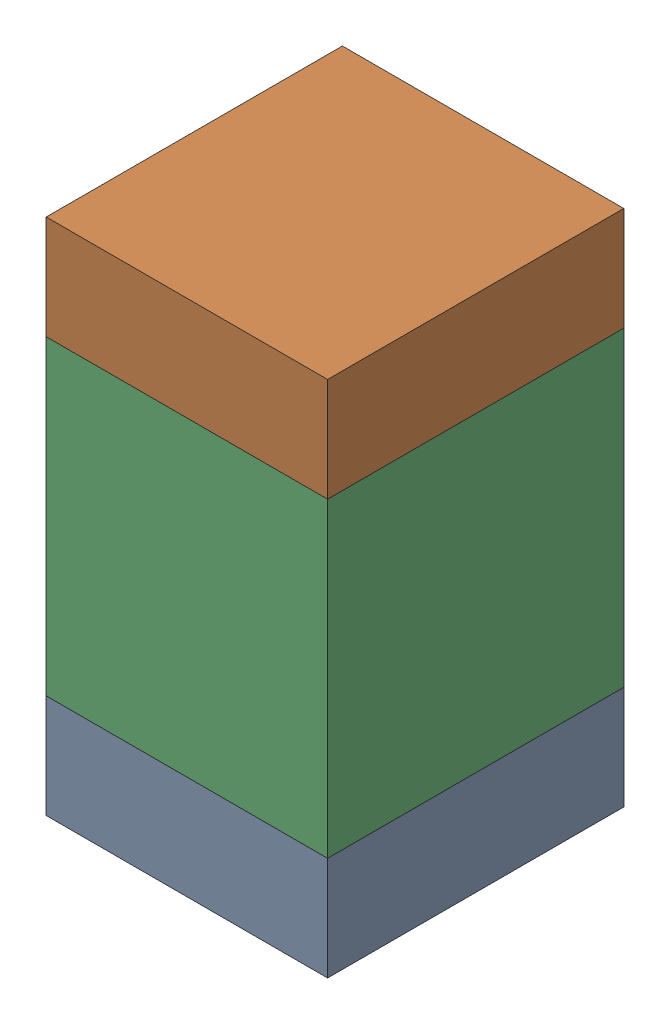
SolidWorks assembly C2-2, configuration Default. Lengths in mm.
Overall size (0.95 1.75 1).
6 component instances, 2 part files, 0 mates.
Components (placement in the parent):
- 959208664-2-1: 959208664-2 [Default] at (140.8925 85.698 0) size (0.95 0.35 1)
  - Extruded-76-1: Extruded-76 [Default] at origin size (0.95 0.35 1)
- 959208664-2-2: 959208664-2 [Default] at (140.8925 87.098 0) size (0.95 0.35 1)
  - Extruded-76-1: Extruded-76 [Default] at origin size (0.95 0.35 1)
- 959208528-2-1: 959208528-2 [Default] at (140.8925 86.398 0) size (0.95 1.05 1)
  - Extruded-77-1: Extruded-77 [Default] at origin size (0.95 1.05 1)
